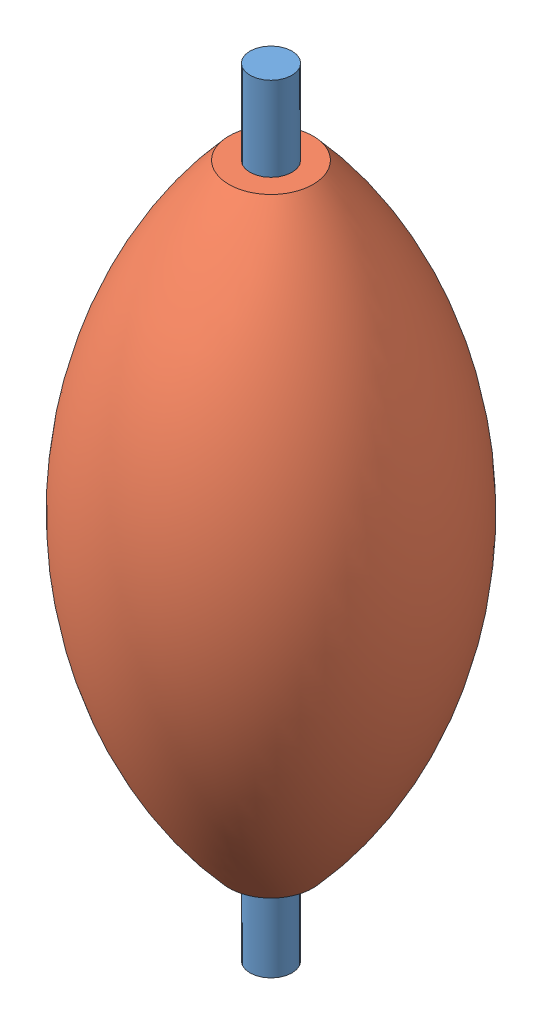
SolidWorks assembly sub_assem, configuration Default. Lengths in mm.
Overall size (6.14 18.5 6.14).
2 component instances, 2 part files, 2 mates.
Components (placement in the parent):
- rod-1: rod [Default] at (8.8671 2.7878 11.5459) size (1 18.5 1)
- roller-1: roller [Default] at (8.8671 2.7878 11.5459) size (6.14 10 6.14)
Mates (geometry in assembly coordinates):
- Concentric1: concentric anti-aligned: cylinder of rod-1 through (8.8671 12.0378 11.5459) axis (0 -1 0) radius 0.5; cylinder of roller-1 through (8.8671 -2.2122 11.5459) axis (0 1 0) radius 0.5
- Coincident3: coincident aligned: plane of rod-1 through (8.8671 2.7878 11.5459) normal (0 1 0); plane of roller-1 through (8.8671 2.7878 11.5459) normal (0 1 0)
